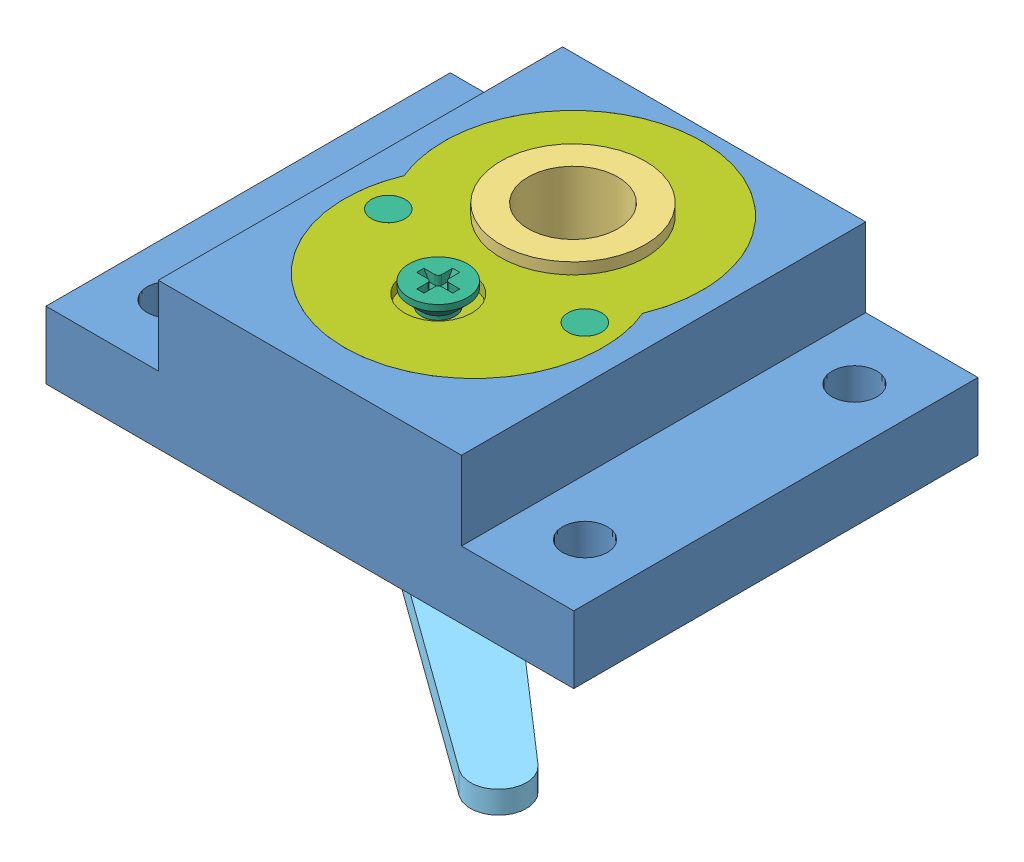
SolidWorks assembly 装配体棘轮2, configuration 默认. Lengths in mm.
Overall size (53.55 16 48).
10 component instances, 7 part files, 22 mates.
Components (placement in the parent):
- 棘轮壳-1: 棘轮壳 [默认] at origin size (47 13 36)
- 棘轮顶片右-1: 棘轮顶片右 [默认] at (2.7 11 10.7323) x (-0.777454 0 0.62894) z (0 -1 0) size (11.42 7.53 11)
- 棘轮轮齿-1: 棘轮轮齿 [默认] at (0 14 -7.7) x (-0.756623 0 0.653851) z (0.653851 0 0.756623) size (17.03 14 17.02)
- 棘轮顶片-2: 棘轮顶片 [默认] at (-2.7 3 10.7323) x (0.641267 0 0.767318) z (0 1 0) size (11.42 7.53 11)
- 棘轮凸轮-1: 棘轮凸轮 [默认] at (0 3 4.3) x (0.998151 0 0.060788) z (0 1 0) size (33.86 25.66 8)
- 棘轮盖板-1: 棘轮盖板 [默认] at (0 11 -7.7) x (1 0 0) z (0 1 0) size (23 31.84 2) (hidden)
- cross recessed countersunk head screws gb2-6: cross recessed countersunk head screws gb2 [GB_CROSS_SCREWS_TYPE10 M3X14-12.35-H1-N] at (-8.75 -1 0) x (0 1 0) z (0.24814 0 0.968724) size (14 5.2 5.2)
- cross recessed countersunk head screws gb2-7: cross recessed countersunk head screws gb2 [GB_CROSS_SCREWS_TYPE10 M3X14-12.35-H1-N] at (8.75 -1 0) x (0 1 0) z (0 0 1) size (14 5.2 5.2)
- cross recessed countersunk head screws gb2-8: cross recessed countersunk head screws gb2 [GB_CROSS_SCREWS_TYPE10 M3X8-6.35-H1-N] at (0 14 4.3) x (0 -1 0) z (0 0 1) size (8 5.2 5.2)
- 棘轮盖板-2: 棘轮盖板 [默认] at (0 11 -7.7) x (1 0 0) z (0 1 0) size (23 31.84 2)
Mates (geometry in assembly coordinates):
- 重合2: coincident anti-aligned: plane of 棘轮壳-1 through (0 3 0) normal (0 1 0); plane of 棘轮轮齿-1 through (-4.8727 3 -3.4892) normal (0 -1 0)
- 同心2: concentric aligned: cylinder of 棘轮壳-1 through (0 3 -7.7) axis (0 -1 0) radius 6.75; cylinder of 棘轮轮齿-1 through (0 -3 -7.7) axis (0 -1 0) radius 6.44
- 同心3: concentric anti-aligned: cylinder of 棘轮壳-1 through (2.7 3 10.7323) axis (0 -1 0) radius 1.5; cylinder of 棘轮顶片右-1 through (2.7 3 10.7323) axis (0 1 0) radius 1.4
- 重合3: coincident anti-aligned: plane of 棘轮壳-1 through (0 3 0) normal (0 1 0); plane of 棘轮顶片右-1 through (4.9372 3 9.8633) normal (0 -1 0)
- 同心4: concentric aligned: cylinder of 棘轮壳-1 through (-2.7 3 10.7323) axis (0 -1 0) radius 1.5; cylinder of 棘轮顶片-2 through (-2.7 11 10.7323) axis (0 -1 0) radius 1.4
- 重合4: coincident anti-aligned: plane of 棘轮壳-1 through (0 3 0) normal (0 1 0); plane of 棘轮顶片-2 through (-4.7271 3 9.4474) normal (0 -1 0)
- 同心5: concentric anti-aligned: cylinder of 棘轮壳-1 through (0 3 4.3) axis (0 -1 0) radius 1.5; cylinder of 棘轮凸轮-1 through (0 0 4.3) axis (0 1 0) radius 1.5
- 重合5: coincident anti-aligned: plane of 棘轮壳-1 through (0 3 0) normal (0 1 0); plane of 棘轮凸轮-1 through (0 3 4.3) normal (0 -1 0)
- 相切1: tangent anti-aligned: plane of 棘轮顶片-2 through (-1.3208 11 10.4919) normal (0.98515 0 -0.171695); cylinder of 棘轮凸轮-1 through (-0.7828 6 3.6777) axis (0 -1 0) radius 1.7
- 相切2: tangent anti-aligned: plane of 棘轮顶片右-1 through (1.3932 3 10.2299) normal (-0.933405 0 -0.358824); cylinder of 棘轮凸轮-1 through (-0.4691 6 3.927) axis (0 -1 0) radius 4
- 同心6: concentric aligned: cylinder of 棘轮轮齿-1 through (0 -3 -7.7) axis (0 -1 0) radius 6.44; cylinder of 棘轮盖板-1 through (0 13 -7.7) axis (0 -1 0) radius 6.44
- 同心7: concentric anti-aligned: cylinder of 棘轮壳-1 through (8.75 3 0) axis (0 -1 0) radius 1.25; cylinder of cross recessed countersunk head screws gb2-7 through (8.75 3.5158 0) axis (0 1 0) radius 1.5
- 重合8: coincident aligned: plane of 棘轮盖板-1 through (0 13 -7.7) normal (0 1 0); plane of cross recessed countersunk head screws gb2-7 through (7.25 13 0) normal (0 1 0)
- 同心8: concentric anti-aligned: cylinder of 棘轮壳-1 through (-8.75 3 0) axis (0 -1 0) radius 1.25; cylinder of cross recessed countersunk head screws gb2-6 through (-8.75 3.5158 0) axis (0 1 0) radius 1.5
- 重合9: coincident aligned: plane of 棘轮盖板-1 through (0 13 -7.7) normal (0 1 0); plane of cross recessed countersunk head screws gb2-6 through (-10.2031 13 0.3722) normal (0 1 0)
- 同心9: concentric aligned: cylinder of 棘轮盖板-1 through (0 13 4.3) axis (0 -1 0) radius 1.5; cylinder of cross recessed countersunk head screws gb2-8 through (0 9.4842 4.3) axis (0 -1 0) radius 1.5
- 重合10: coincident anti-aligned: plane of 棘轮凸轮-1 through (0 6 4.3) normal (0 1 0); plane of cross recessed countersunk head screws gb2-8 through (1.5 6 4.3) normal (0 -1 0)
- 同心10: concentric aligned: cylinder of 棘轮壳-1 through (0 11 1.1386) axis (0 1 0) radius 11.5; cylinder of 棘轮盖板-1 through (0 11 1.1386) axis (0 1 0) radius 11.5
- 重合11: coincident anti-aligned: plane of 棘轮壳-1 through (0 11 -3.2807) normal (0 1 0); plane of 棘轮盖板-1 through (0 11 -7.7) normal (0 -1 0)
- 重合12: coincident anti-aligned: plane of 棘轮壳-1 through (0 11 -3.2807) normal (0 1 0); plane of 棘轮盖板-2 through (0 11 -7.7) normal (0 -1 0)
- 同心11: concentric aligned: cylinder of 棘轮轮齿-1 through (0 -3 -7.7) axis (0 -1 0) radius 6.44; cylinder of 棘轮盖板-2 through (0 13 -7.7) axis (0 -1 0) radius 6.44
- 同心12: concentric anti-aligned: cylinder of cross recessed countersunk head screws gb2-6 through (-8.75 3.5158 0) axis (0 1 0) radius 1.5; cylinder of 棘轮盖板-2 through (-8.75 13 0) axis (0 -1 0) radius 1.5
